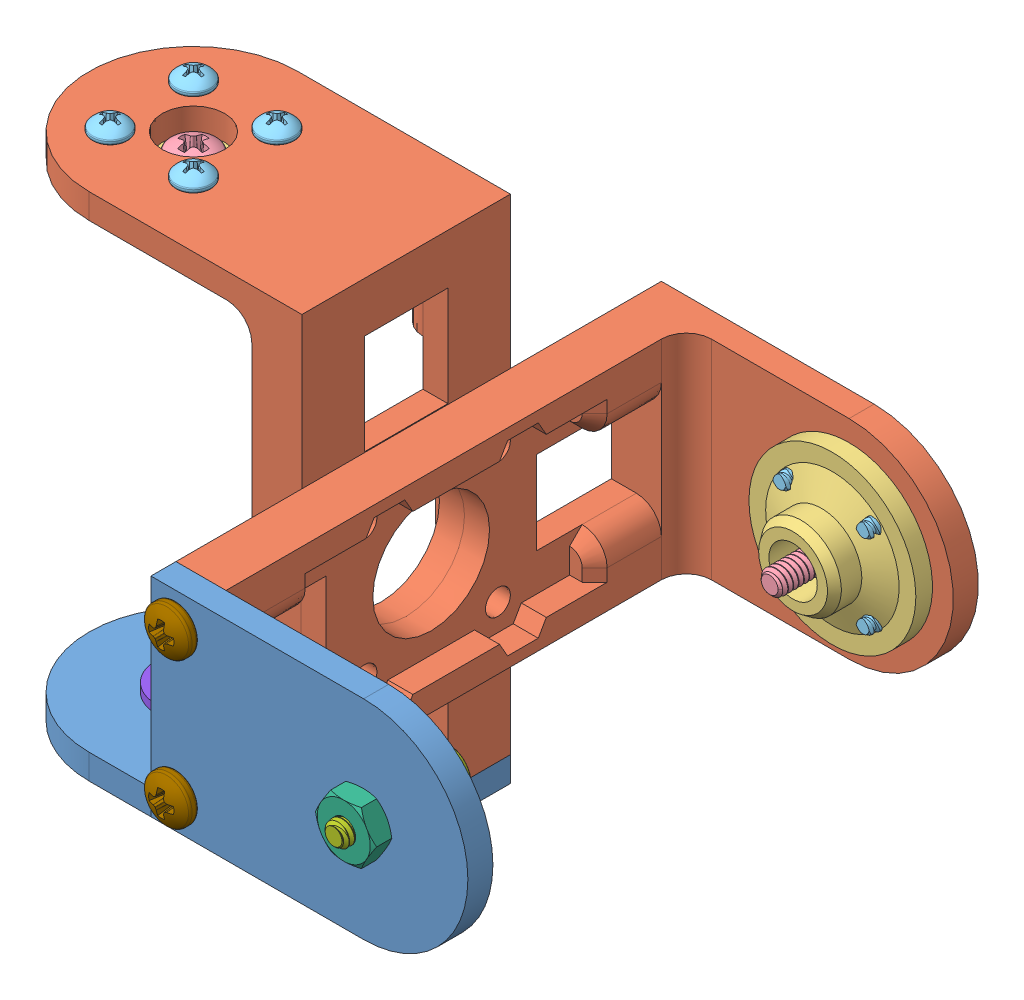
SolidWorks assembly DATUI, configuration 默认. Lengths in mm.
Overall size (76 79.05 69.62).
24 component instances, 9 part files, 67 mates.
Components (placement in the parent):
- 复件 Femur Bracket-0^DATUI-1: 复件 Femur Bracket-0^DATUI [默认] at (-21.6477 -5.7056 0) x (0 0 1) z (0 -1 0) size (25 38 3) (virtual)
- 复件 Femur Bracket-1^DATUI-1: 复件 Femur Bracket-1^DATUI [默认] at (-21.6477 -5.7056 0) x (0 0 1) z (0 -1 0) size (25 38 58.2) (virtual)
- 复件 Femur Bracket-1^DATUI-2: 复件 Femur Bracket-1^DATUI [默认] at (21.6477 0 5.7056) x (0 -1 0) z (0 0 1) size (25 38 58.2) (virtual)
- 复件 Femur Bracket-0^DATUI-2: 复件 Femur Bracket-0^DATUI [默认] at (21.6477 0 5.7056) x (0 -1 0) z (0 0 1) size (25 38 3) (virtual)
- 复件 Servo Wheel^DATUI-1: 复件 Servo Wheel^DATUI [默认] at (-34.9039 -28.8783 -3.4) x (0 0 -1) z (1 0 0) size (20 6.72 20) (virtual)
- 复件 Servo Wheel^DATUI-2: 复件 Servo Wheel^DATUI [默认] at (34.9039 3.4 28.8783) x (0 1 0) z (-1 0 0) size (20 6.72 20) (virtual)
- 复件 4-40 x 0.375^DATUI-1: 复件 4-40 x 0.375^DATUI [默认] at (-25.5 18.075 0) x (-1 0 0) z (0 1 0) size (5.56 5.56 11.49) (virtual)
- 复件 4-40 x 0.375^DATUI-2: 复件 4-40 x 0.375^DATUI [默认] at (25.5 0 -18.075) x (-1 0 0) z (0 0 -1) size (5.56 5.56 11.49) (virtual)
- 复件 Blunt #2 0.25^DATUI-1: 复件 Blunt #2 0.25^DATUI [默认] at (-30.5 27.425 5) x (-1 0 0) z (0 1 0) size (4.24 4.24 7.89) (virtual)
- 复件 Blunt #2 0.25^DATUI-2: 复件 Blunt #2 0.25^DATUI [默认] at (-30.5 27.425 -5) x (-1 0 0) z (0 1 0) size (4.24 4.24 7.89) (virtual)
- 复件 Blunt #2 0.25^DATUI-3: 复件 Blunt #2 0.25^DATUI [默认] at (-20.5 27.425 -5) x (1 0 0) z (0 1 0) size (4.24 4.24 7.89) (virtual)
- 复件 Blunt #2 0.25^DATUI-4: 复件 Blunt #2 0.25^DATUI [默认] at (-20.5 27.425 5) x (-1 0 0) z (0 1 0) size (4.24 4.24 7.89) (virtual)
- 复件 Blunt #2 0.25^DATUI-5: 复件 Blunt #2 0.25^DATUI [默认] at (20.5 5 -27.425) x (-1 0 0) z (0 0 -1) size (4.24 4.24 7.89) (virtual)
- 复件 Blunt #2 0.25^DATUI-6: 复件 Blunt #2 0.25^DATUI [默认] at (30.5 -5 -27.425) x (-1 0 0) z (0 0 -1) size (4.24 4.24 7.89) (virtual)
- 复件 Blunt #2 0.25^DATUI-7: 复件 Blunt #2 0.25^DATUI [默认] at (20.5 -5 -27.425) x (-1 0 0) z (0 0 -1) size (4.24 4.24 7.89) (virtual)
- 复件 Blunt #2 0.25^DATUI-8: 复件 Blunt #2 0.25^DATUI [默认] at (30.5 5 -27.425) x (-1 0 0) z (0 0 -1) size (4.24 4.24 7.89) (virtual)
- 复件 4-40 Nut^DATUI-1: 复件 4-40 Nut^DATUI [默认] at (-25.5 -31.7906 0) x (0.866025 0 0.5) z (-0.5 0 0.866025) size (6.35 2.39 7.33) (virtual)
- 复件 4-40 Nut^DATUI-2: 复件 4-40 Nut^DATUI [默认] at (25.5 0 31.7906) x (0.866025 -0.5 0) z (-0.5 -0.866025 0) size (6.35 2.39 7.33) (virtual)
- 复件 4-40 x 0.500^DATUI-1: 复件 4-40 x 0.500^DATUI [默认] at (-25.5 -34.2 0) x (1 0 0) z (0 1 0) size (5.56 5.56 14.67) (virtual)
- 复件 Bearing Center^DATUI-1: 复件 Bearing Center^DATUI [默认] at (-25.5 -27.6 0) size (9 6 9) (virtual)
- 复件 Bearing Center^DATUI-2: 复件 Bearing Center^DATUI [默认] at (25.5 0 27.6) x (1 0 0) z (0 1 0) size (9 6 9) (virtual)
- 复件 4-40 x 0.500^DATUI-2: 复件 4-40 x 0.500^DATUI [默认] at (25.5 0 34.2) x (1 0 0) z (0 0 -1) size (5.56 5.56 14.67) (virtual)
- 复件 (2) 4-40 x 0.500^DATUI-1: 复件 (2) 4-40 x 0.500^DATUI [默认] at (3 8.75 17.9) x (-1 0 0) z (0 0 1) size (5.56 5.56 14.67) (virtual)
- 复件 (2) 4-40 x 0.500^DATUI-2: 复件 (2) 4-40 x 0.500^DATUI [默认] at (3 -8.75 17.9) x (0 -1 0) z (0 0 1) size (5.56 5.56 14.67) (virtual)
Mates (geometry in assembly coordinates):
- 重合1: coincident: plane of 复件 Femur Bracket-0^DATUI-1 through (0 -27.6 0) normal (0 1 0); plane of 复件 Femur Bracket-1^DATUI-1 through (-3 -27.6 0) normal (0 -1 0)
- 同心1: concentric: cylinder of 复件 Femur Bracket-0^DATUI-1 through (-3 -30.6 -8.75) axis (0 1 0) radius 1.5; cylinder of 复件 Femur Bracket-1^DATUI-1 through (-3 -30.6 -8.75) axis (0 1 0) radius 1.13
- 同心2: concentric: cylinder of 复件 Femur Bracket-0^DATUI-1 through (-3 -30.6 8.75) axis (0 1 0) radius 1.5; cylinder of 复件 Femur Bracket-1^DATUI-1 through (-3 -30.6 8.75) axis (0 1 0) radius 1.13
- 重合2: coincident: plane of 复件 Femur Bracket-1^DATUI-2 through (3 0 27.6) normal (0 0 1); plane of 复件 Femur Bracket-0^DATUI-2 through (0 0 27.6) normal (0 0 -1)
- 同心3: concentric: cylinder of 复件 Femur Bracket-1^DATUI-2 through (3 8.75 30.6) axis (0 0 -1) radius 1.13; cylinder of 复件 Femur Bracket-0^DATUI-2 through (3 8.75 30.6) axis (0 0 -1) radius 1.5
- 同心4: concentric: cylinder of 复件 Femur Bracket-1^DATUI-2 through (3 -8.75 30.6) axis (0 0 -1) radius 1.13; cylinder of 复件 Femur Bracket-0^DATUI-2 through (3 -8.75 30.6) axis (0 0 -1) radius 1.5
- 重合3: coincident: plane of 复件 Femur Bracket-1^DATUI-1 through (0 -27.6 0) normal (1 0 0); plane of 复件 Femur Bracket-1^DATUI-2 through (0 0 27.6) normal (-1 0 0)
- 同心6: concentric: cylinder of 复件 Femur Bracket-1^DATUI-1 through (0 -8 8) axis (-1 0 0) radius 1.5; cylinder of 复件 Femur Bracket-1^DATUI-2 through (0 -8 8) axis (1 0 0) radius 1.5
- 同心7: concentric: cylinder of 复件 Femur Bracket-1^DATUI-1 through (0 -8 -8) axis (-1 0 0) radius 1.5; cylinder of 复件 Femur Bracket-1^DATUI-2 through (0 -8 -8) axis (1 0 0) radius 1.5
- 重合4: coincident: plane of 复件 Femur Bracket-1^DATUI-1 through (-38 27.6 0) normal (0 -1 0); plane of 复件 Servo Wheel^DATUI-1 through (-15.5 27.6 0) normal (0 1 0)
- 同心8: concentric: cylinder of 复件 Femur Bracket-1^DATUI-1 through (-25.5 30.6 0) axis (0 -1 0) radius 3.75; cylinder of 复件 Servo Wheel^DATUI-1 through (-25.5 27.6 0) axis (0 -1 0) radius 1.25
- 平行1: parallel: plane of 复件 Femur Bracket-1^DATUI-1 through (-6 0 0) normal (-1 0 0); plane of 复件 Servo Wheel^DATUI-1 through (-34.9039 -28.8783 -3.4) normal (1 0 0)
- 重合9: coincident: plane of 复件 Femur Bracket-1^DATUI-2 through (38 0 -27.6) normal (0 0 1); plane of 复件 Servo Wheel^DATUI-2 through (15.5 0 -27.6) normal (0 0 -1)
- 同心9: concentric: cylinder of 复件 Femur Bracket-1^DATUI-2 through (25.5 0 -30.6) axis (0 0 1) radius 3.75; cylinder of 复件 Servo Wheel^DATUI-2 through (25.5 0 -25.6) axis (0 0 1) radius 2.9
- 平行2: parallel: plane of 复件 Femur Bracket-1^DATUI-2 through (6 0 0) normal (1 0 0); plane of 复件 Servo Wheel^DATUI-2 through (34.9039 3.4 28.8783) normal (-1 0 0)
- 同心10: concentric: cylinder of 复件 Servo Wheel^DATUI-1 through (-25.5 27.6 0) axis (0 -1 0) radius 1.25; cylinder of 复件 4-40 x 0.375^DATUI-1 through (-25.5 18.075 0) axis (0 -1 0) radius 2.7813
- 重合11: coincident: plane of 复件 Servo Wheel^DATUI-1 through (-15.5 27.6 0) normal (0 1 0); plane of 复件 4-40 x 0.375^DATUI-1 through (-25.5 27.6 0) normal (0 -1 0)
- 同心11: concentric: cylinder of 复件 Servo Wheel^DATUI-2 through (25.5 0 -25.6) axis (0 0 1) radius 2.9; cylinder of 复件 4-40 x 0.375^DATUI-2 through (25.5 0 -18.075) axis (0 0 1) radius 2.7813
- 重合12: coincident: plane of 复件 Servo Wheel^DATUI-2 through (15.5 0 -27.6) normal (0 0 -1); plane of 复件 4-40 x 0.375^DATUI-2 through (25.5 0 -27.6) normal (0 0 1)
- 同心12: concentric: cylinder of 复件 Femur Bracket-1^DATUI-1 through (-30.5 30.6 5) axis (0 -1 0) radius 1.2; cylinder of 复件 Blunt #2 0.25^DATUI-1 through (-30.5 32.1748 5) axis (0 -1 0) radius 2.1209
- 重合14: coincident: plane of 复件 Femur Bracket-1^DATUI-1 through (0 30.6 0) normal (0 1 0); plane of 复件 Blunt #2 0.25^DATUI-1 through (-30.5 30.6 5) normal (0 -1 0)
- 平行5: parallel: plane of 复件 Femur Bracket-1^DATUI-1 through (-19 1.5 12.5) normal (0 0 1); plane of 复件 4-40 x 0.375^DATUI-1 through (-25.5 18.075 0) normal (0 0 1)
- 平行6: parallel: plane of 复件 Femur Bracket-1^DATUI-1 through (-19 1.5 12.5) normal (0 0 1); plane of 复件 Blunt #2 0.25^DATUI-1 through (-30.5 27.425 5) normal (0 0 1)
- 平行7: parallel: plane of 复件 Femur Bracket-1^DATUI-2 through (19 12.5 -1.5) normal (0 1 0); plane of 复件 4-40 x 0.375^DATUI-2 through (25.5 0 -18.075) normal (0 1 0)
- 同心13: concentric: cylinder of 复件 Femur Bracket-1^DATUI-1 through (-30.5 30.6 -5) axis (0 -1 0) radius 1.2; cylinder of 复件 Blunt #2 0.25^DATUI-2 through (-30.5 32.1748 -5) axis (0 -1 0) radius 2.1209
- 重合17: coincident: plane of 复件 Femur Bracket-1^DATUI-1 through (0 30.6 0) normal (0 1 0); plane of 复件 Blunt #2 0.25^DATUI-2 through (-30.5 30.6 -5) normal (0 -1 0)
- 同心14: concentric: cylinder of 复件 Femur Bracket-1^DATUI-1 through (-20.5 30.6 -5) axis (0 -1 0) radius 1.2; cylinder of 复件 Blunt #2 0.25^DATUI-3 through (-20.5 32.1748 -5) axis (0 -1 0) radius 2.1209
- 重合18: coincident: plane of 复件 Femur Bracket-1^DATUI-1 through (0 30.6 0) normal (0 1 0); plane of 复件 Blunt #2 0.25^DATUI-3 through (-20.5 30.6 -5) normal (0 -1 0)
- 同心15: concentric: cylinder of 复件 Femur Bracket-1^DATUI-1 through (-20.5 30.6 5) axis (0 -1 0) radius 1.2; cylinder of 复件 Blunt #2 0.25^DATUI-4 through (-20.5 32.1748 5) axis (0 -1 0) radius 2.1209
- 重合19: coincident: plane of 复件 Femur Bracket-1^DATUI-1 through (0 30.6 0) normal (0 1 0); plane of 复件 Blunt #2 0.25^DATUI-4 through (-20.5 30.6 5) normal (0 -1 0)
- 平行8: parallel: plane of 复件 Femur Bracket-1^DATUI-1 through (-19 1.5 12.5) normal (0 0 1); plane of 复件 Blunt #2 0.25^DATUI-2 through (-30.5 27.425 -5) normal (0 0 1)
- 平行9: parallel: plane of 复件 Femur Bracket-1^DATUI-1 through (-19 1.5 12.5) normal (0 0 1); plane of 复件 Blunt #2 0.25^DATUI-3 through (-20.5 27.425 -5) normal (0 0 -1)
- 平行10: parallel: plane of 复件 Femur Bracket-1^DATUI-1 through (-19 1.5 12.5) normal (0 0 1); plane of 复件 Blunt #2 0.25^DATUI-4 through (-20.5 27.425 5) normal (0 0 1)
- 同心16: concentric: cylinder of 复件 Femur Bracket-1^DATUI-2 through (20.5 5 -30.6) axis (0 0 1) radius 1.2; cylinder of 复件 Blunt #2 0.25^DATUI-5 through (20.5 5 -32.1748) axis (0 0 1) radius 2.1209
- 重合23: coincident: plane of 复件 Femur Bracket-1^DATUI-2 through (0 0 -30.6) normal (0 0 -1); plane of 复件 Blunt #2 0.25^DATUI-5 through (20.5 5 -30.6) normal (0 0 1)
- 平行11: parallel: plane of 复件 Femur Bracket-1^DATUI-2 through (19 12.5 -1.5) normal (0 1 0); plane of 复件 Blunt #2 0.25^DATUI-5 through (20.5 5 -27.425) normal (0 1 0)
- 同心17: concentric: cylinder of 复件 Femur Bracket-1^DATUI-2 through (20.5 -5 -30.6) axis (0 0 1) radius 1.2; cylinder of 复件 Blunt #2 0.25^DATUI-7 through (20.5 -5 -32.1748) axis (0 0 1) radius 2.1209
- 重合25: coincident: plane of 复件 Femur Bracket-1^DATUI-2 through (0 0 -30.6) normal (0 0 -1); plane of 复件 Blunt #2 0.25^DATUI-7 through (20.5 -5 -30.6) normal (0 0 1)
- 同心18: concentric: cylinder of 复件 Femur Bracket-1^DATUI-2 through (30.5 -5 -30.6) axis (0 0 1) radius 1.2; cylinder of 复件 Blunt #2 0.25^DATUI-6 through (30.5 -5 -32.1748) axis (0 0 1) radius 2.1209
- 重合26: coincident: plane of 复件 Femur Bracket-1^DATUI-2 through (0 0 -30.6) normal (0 0 -1); plane of 复件 Blunt #2 0.25^DATUI-6 through (30.5 -5 -30.6) normal (0 0 1)
- 同心19: concentric: cylinder of 复件 Femur Bracket-1^DATUI-2 through (30.5 5 -30.6) axis (0 0 1) radius 1.2; cylinder of 复件 Blunt #2 0.25^DATUI-8 through (30.5 5 -32.1748) axis (0 0 1) radius 2.1209
- 重合27: coincident: plane of 复件 Femur Bracket-1^DATUI-2 through (0 0 -30.6) normal (0 0 -1); plane of 复件 Blunt #2 0.25^DATUI-8 through (30.5 5 -30.6) normal (0 0 1)
- 平行12: parallel: plane of 复件 Femur Bracket-1^DATUI-2 through (19 12.5 -1.5) normal (0 1 0); plane of 复件 Blunt #2 0.25^DATUI-6 through (30.5 -5 -27.425) normal (0 1 0)
- 平行13: parallel: plane of 复件 Femur Bracket-1^DATUI-2 through (19 12.5 -1.5) normal (0 1 0); plane of 复件 Blunt #2 0.25^DATUI-7 through (20.5 -5 -27.425) normal (0 1 0)
- 平行14: parallel: plane of 复件 Femur Bracket-1^DATUI-2 through (19 12.5 -1.5) normal (0 1 0); plane of 复件 Blunt #2 0.25^DATUI-8 through (30.5 5 -27.425) normal (0 1 0)
- 同心20: concentric: cylinder of 复件 Femur Bracket-0^DATUI-1 through (-25.5 -30.6 0) axis (0 1 0) radius 1.5; circle of 复件 4-40 Nut^DATUI-1
- 重合31: coincident: plane of 复件 Femur Bracket-0^DATUI-1 through (-38 -30.6 0) normal (0 -1 0); plane of 复件 4-40 Nut^DATUI-1 through (-27.3331 -30.6 -3.175) normal (0 1 0)
- 平行15: parallel: plane of 复件 Femur Bracket-0^DATUI-1 through (-19 -29.1 12.5) normal (0 0 1); plane of 复件 4-40 Nut^DATUI-1 through (-27.3331 -30.6 3.175) normal (0 0 1)
- 同心21: concentric: cylinder of 复件 Femur Bracket-0^DATUI-2 through (25.5 0 30.6) axis (0 0 -1) radius 1.5; circle of 复件 4-40 Nut^DATUI-2
- 重合33: coincident: plane of 复件 Femur Bracket-0^DATUI-2 through (38 0 30.6) normal (0 0 1); plane of 复件 4-40 Nut^DATUI-2 through (23.6669 3.175 30.6) normal (0 0 -1)
- 平行16: parallel: plane of 复件 Femur Bracket-0^DATUI-2 through (19 -12.5 29.1) normal (0 -1 0); plane of 复件 4-40 Nut^DATUI-2 through (23.6669 -3.175 32.9812) normal (0 -1 0)
- 同心22: concentric: circle of 复件 4-40 Nut^DATUI-1; cylinder of 复件 4-40 x 0.500^DATUI-1 through (-25.5 -34.2 0) axis (0 -1 0) radius 2.7813
- 距离1: distance = 3.6 mm: plane of 复件 4-40 x 0.500^DATUI-1 through (-25.5 -34.2 0) normal (0 -1 0); plane of 复件 Femur Bracket-0^DATUI-1 through (-38 -30.6 0) normal (0 -1 0)
- 平行17: parallel: plane of 复件 Femur Bracket-0^DATUI-1 through (-19 -29.1 12.5) normal (0 0 1); plane of 复件 4-40 x 0.500^DATUI-1 through (-25.5 -34.2 0) normal (0 0 -1)
- 重合37: coincident: plane of 复件 Femur Bracket-0^DATUI-1 through (0 -27.6 0) normal (0 1 0); plane of 复件 Bearing Center^DATUI-1 through (-25.5 -27.6 0) normal (0 -1 0)
- 同心23: concentric: cylinder of 复件 4-40 x 0.500^DATUI-1 through (-25.5 -34.2 0) axis (0 -1 0) radius 2.7813; cylinder of 复件 Bearing Center^DATUI-1 through (-25.5 -27.6 0) axis (0 1 0) radius 2.05
- 同心24: concentric: cylinder of 复件 Femur Bracket-0^DATUI-2 through (25.5 0 30.6) axis (0 0 -1) radius 1.5; cylinder of 复件 4-40 x 0.500^DATUI-2 through (25.5 0 34.2) axis (0 0 1) radius 2.7813
- 距离2: distance = 3.6 mm: plane of 复件 Femur Bracket-0^DATUI-2 through (38 0 30.6) normal (0 0 1); plane of 复件 4-40 x 0.500^DATUI-2 through (25.5 0 34.2) normal (0 0 1)
- 平行18: parallel: plane of 复件 Femur Bracket-0^DATUI-2 through (19 12.5 29.1) normal (0 1 0); plane of 复件 4-40 x 0.500^DATUI-2 through (25.5 0 34.2) normal (0 -1 0)
- 同心25: concentric: cylinder of 复件 Bearing Center^DATUI-2 through (25.5 0 27.6) axis (0 0 -1) radius 2.05; cylinder of 复件 4-40 x 0.500^DATUI-2 through (25.5 0 34.2) axis (0 0 1) radius 2.7813
- 重合40: coincident: plane of 复件 Femur Bracket-0^DATUI-2 through (0 0 27.6) normal (0 0 -1); plane of 复件 Bearing Center^DATUI-2 through (25.5 0 27.6) normal (0 0 1)
- 同心26: concentric: cylinder of 复件 Femur Bracket-0^DATUI-2 through (3 8.75 30.6) axis (0 0 -1) radius 1.5; cylinder of 复件 (2) 4-40 x 0.500^DATUI-1 through (3 8.75 17.9) axis (0 0 -1) radius 2.7813
- 重合41: coincident: plane of 复件 Femur Bracket-0^DATUI-2 through (38 0 30.6) normal (0 0 1); plane of 复件 (2) 4-40 x 0.500^DATUI-1 through (3 8.75 30.6) normal (0 0 -1)
- 平行19: parallel: plane of 复件 Femur Bracket-1^DATUI-2 through (19 12.5 -1.5) normal (0 1 0); plane of 复件 (2) 4-40 x 0.500^DATUI-1 through (3 8.75 17.9) normal (0 -1 0)
- 同心27: concentric: cylinder of 复件 Femur Bracket-0^DATUI-2 through (3 -8.75 30.6) axis (0 0 -1) radius 1.5; cylinder of 复件 (2) 4-40 x 0.500^DATUI-2 through (3 -8.75 17.9) axis (0 0 -1) radius 2.7813
- 重合43: coincident: plane of 复件 Femur Bracket-0^DATUI-2 through (38 0 30.6) normal (0 0 1); plane of 复件 (2) 4-40 x 0.500^DATUI-2 through (3 -8.75 30.6) normal (0 0 -1)
- 平行20: parallel: plane of 复件 Femur Bracket-0^DATUI-2 through (19 12.5 29.1) normal (0 1 0); plane of 复件 (2) 4-40 x 0.500^DATUI-2 through (3 -8.75 17.9) normal (0 -1 0)
